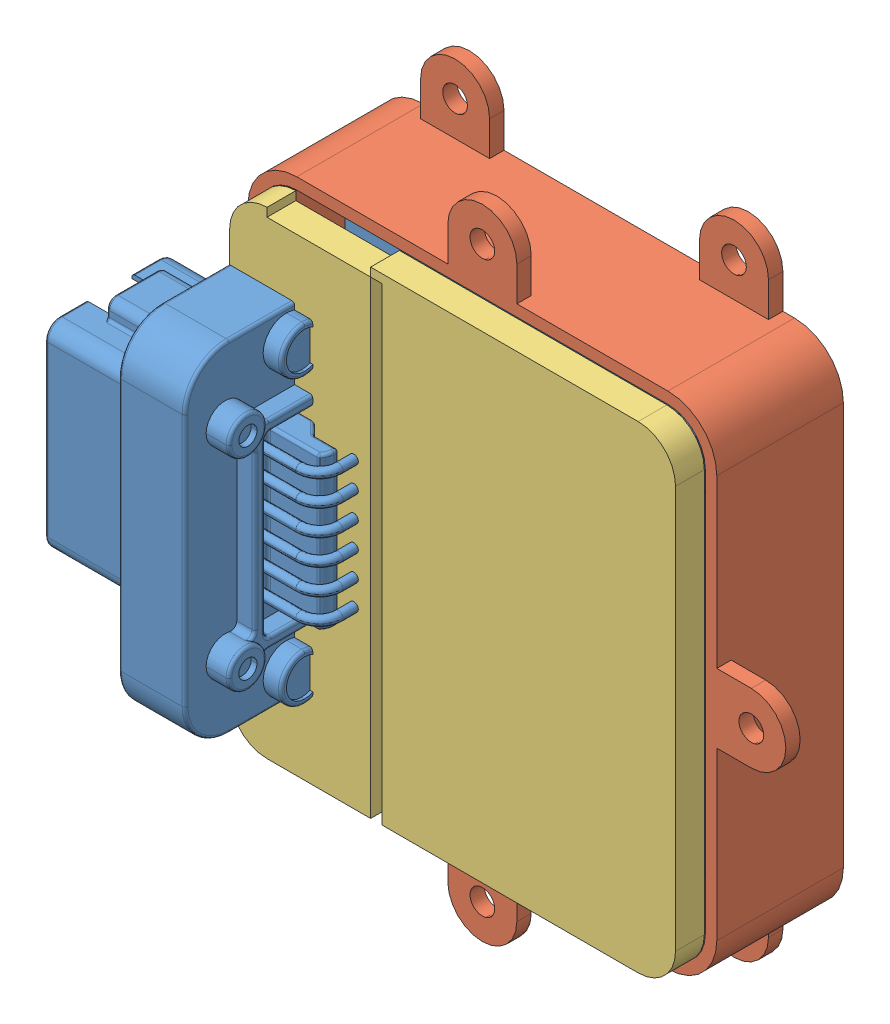
SolidWorks assembly Enclosure, configuration Default. Lengths in mm.
Overall size (111.07 111 46.22).
3 component instances, 3 part files, 0 mates.
Components (placement in the parent):
- PCB.step-2: PCB.step [Default] at (-180.7485 -3.4523 6.4199) size (95.57 80 43.86)
- Part6^Enclosure-1: Part6^Enclosure [Default] at origin size (93.5 111 22) (virtual)
- Part7^Enclosure-1: Part7^Enclosure [Default] at origin size (77.5 83 5) (virtual)
